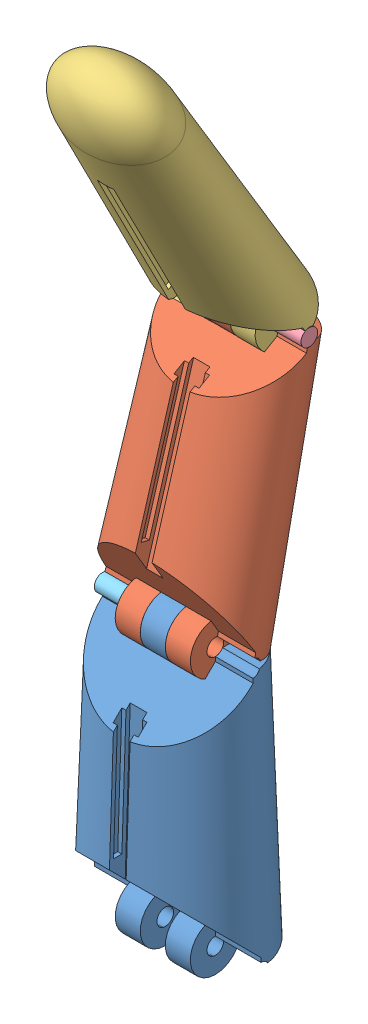
SolidWorks assembly Assem1, configuration Default. Lengths in mm.
Overall size (21.16 99.49 30.3).
5 component instances, 5 part files, 8 mates.
Components (placement in the parent):
- bionic finger mid-1: bionic finger mid [Default] at (-10.6833 5.7482 40.214) size (21.16 37 15.33)
- part2biofinger-1: part2biofinger [Default] at (-10.6833 36.7323 40.0888) x (1 0 0) z (0 0.250462 0.968126) size (18.98 37 13.28)
- part3-1: part3 [Default] at (-10.6833 66.6972 32.6926) x (1 0 0) z (0 -0.485762 0.874091) size (16.85 40.52 11.25)
- mate2-1: mate2 [Default] at (-18.6833 66.2601 32.4497) size (16 2 2)
- mate1-2: mate1 [Default] at (-19.6833 36.2482 40.214) size (9 2 2)
Mates (geometry in assembly coordinates):
- Concentric1: concentric aligned: circle of part2biofinger-1; axis of part3-1 through (-15.1833 66.2601 32.4497) axis (1 0 0)
- Coincident17: coincident aligned: circle of part2biofinger-1; circle of part3-1
- Coincident19: coincident aligned: cylinder of bionic finger mid-1; cylinder of part2biofinger-1 through (-20.1877 36.2482 40.214) axis (1 0 0) radius 1
- Coincident20: coincident anti-aligned: plane of bionic finger mid-1 through (-12.1833 36.2482 40.214) normal (-1 0 0); circle of part2biofinger-1
- Coincident21: coincident aligned: cylinder of part3-1 through (-19.087 66.2601 32.4497) axis (1 0 0) radius 1; circle of mate2-1
- Concentric2: concentric anti-aligned: cylinder of part2biofinger-1 through (-20.1877 36.2482 40.214) axis (1 0 0) radius 1; cylinder of mate1-2 through (-10.6833 36.2482 40.214) axis (-1 0 0) radius 1
- Coincident23: coincident aligned: plane of bionic finger mid-1 through (-10.6833 5.7482 40.214) normal (1 0 0); plane of mate1-2 through (-10.6833 36.2482 40.214) normal (1 0 0)
- Coincident24: coincident aligned: plane of part2biofinger-1 through (-10.6833 36.7323 40.0888) normal (1 0 0); plane of mate2-1 through (-10.6833 66.2601 32.4497) normal (1 0 0)
